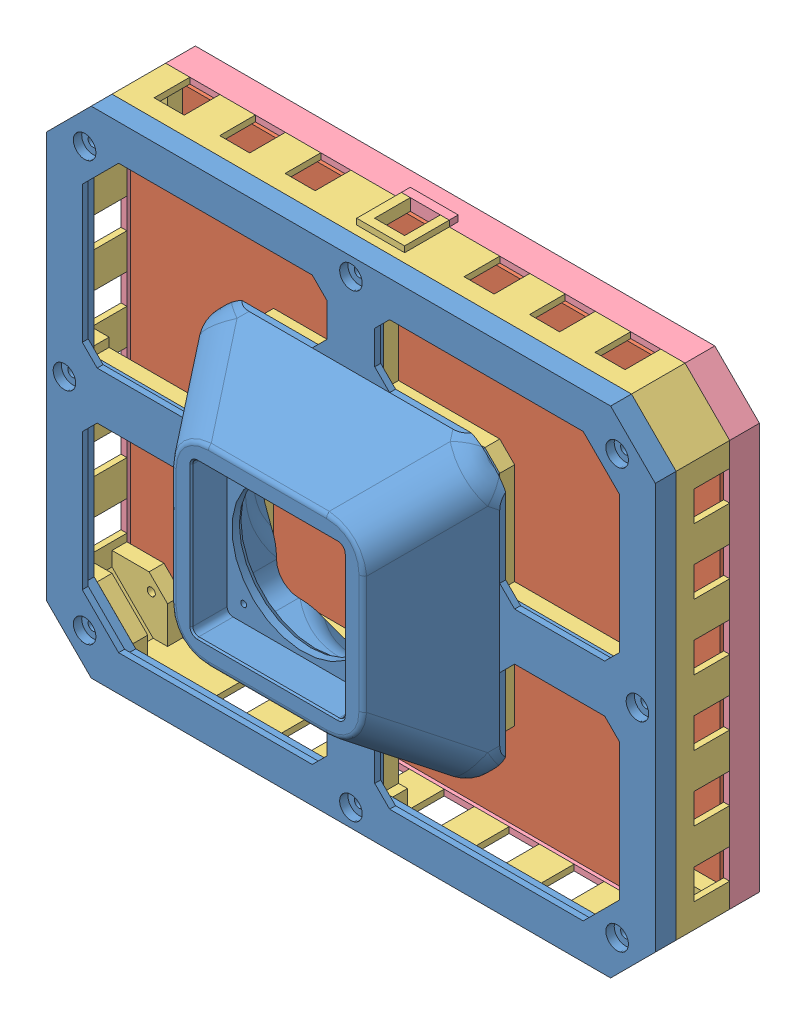
SolidWorks assembly Assemblage1, configuration Défaut. Lengths in mm.
Overall size (204.52 168.42 63).
5 component instances, 5 part files, 9 mates.
Components (placement in the parent):
- couvercle-1: couvercle [Défaut] at (-20.3097 15.2323 204.52) size (204.52 166.42 37.5)
- plexiglass-1: plexiglass [Défaut] at (-56.6224 40.5131 205.52) size (88.26 69.21 0)
- pcb-1: pcb [Défaut] at (-119.3697 95.2423 180.52) size (198.12 160.02 2)
- piece_milieu-1: piece_milieu [Défaut] at (-20.3097 15.2323 182.52) size (204.52 168.42 18)
- plaque_dessous-1: plaque_dessous [Défaut] at (-20.3097 15.2323 172.52) x (-1 0 0) z (0 0 1) size (204.52 168.42 10)
Mates (geometry in assembly coordinates):
- Coïncidente1: coincident anti-aligned: plane of couvercle-1 through (-20.3097 15.2323 200.52) normal (0 0 -1); plane of piece_milieu-1 through (-20.3097 15.2323 200.52) normal (0 0 1)
- Parallèle1: parallel aligned: plane of couvercle-1 through (-122.5697 98.4423 200.52) normal (-1 0 0); plane of piece_milieu-1 through (-122.5697 98.4423 200.52) normal (-1 0 0)
- Coaxiale2: concentric aligned: cylinder of couvercle-1 through (-20.3097 -61.9777 200.52) axis (0 0 1) radius 1.65; cylinder of piece_milieu-1 through (-20.3097 -61.9777 182.52) axis (0 0 1) radius 1.35
- Coïncidente3: coincident anti-aligned: plane of pcb-1 through (-119.3697 95.2423 182.52) normal (0 0 1); plane of piece_milieu-1 through (-20.3097 15.2323 182.52) normal (0 0 -1)
- Coaxiale3: concentric aligned: cylinder of pcb-1 through (-107.3697 83.2423 182.52) axis (0 0 -1) radius 1.6; cylinder of piece_milieu-1 through (-107.3697 83.2423 187.52) axis (0 0 -1) radius 1.35
- Parallèle2: parallel aligned: plane of pcb-1 through (-119.3697 79.8753 182.52) normal (-1 0 0); plane of piece_milieu-1 through (-122.5697 98.4423 200.52) normal (-1 0 0)
- Coïncidente5: coincident anti-aligned: plane of piece_milieu-1 through (-20.3097 15.2323 182.52) normal (0 0 -1); plane of plaque_dessous-1 through (-20.3097 15.2323 182.52) normal (0 0 1)
- Coaxiale4: concentric anti-aligned: cylinder of piece_milieu-1 through (66.7503 83.2423 187.52) axis (0 0 -1) radius 1.35; cylinder of plaque_dessous-1 through (66.7503 83.2423 172.52) axis (0 0 1) radius 1.65
- Coaxiale5: concentric anti-aligned: cylinder of piece_milieu-1 through (-107.3697 -52.7777 187.52) axis (0 0 -1) radius 1.35; cylinder of plaque_dessous-1 through (-107.3697 -52.7777 172.52) axis (0 0 1) radius 1.65
